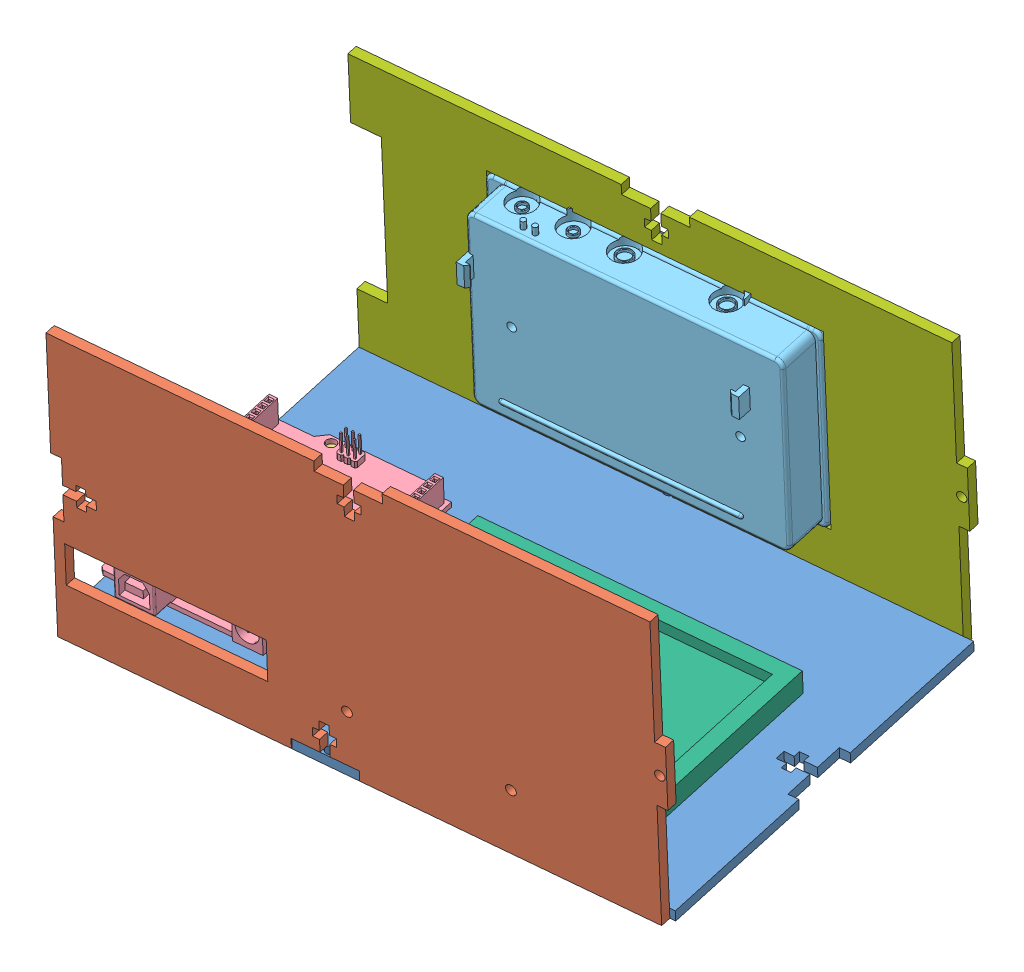
SolidWorks assembly PIDbox.testassembly1, configuration Default. Lengths in mm.
Overall size (201.49 115.17 154.94).
10 component instances, 7 part files, 34 mates.
Components (placement in the parent):
- PIDbox.floor-1: PIDbox.floor [Default] at (-69.6794 29.4727 44.4272) x (0.989177 -0.043479 -0.140136) z (0.057614 0.993474 0.09844) size (180 122.36 3.18)
- PIDbox.frontwall-2: PIDbox.frontwall [Default] at (-57.667 70.483 106.041) x (0.989177 -0.043479 -0.140136) z (0.134941 -0.105448 0.985227) size (180 95 3.18)
- 25x.5 Aluminum Hex Female Female Standoff-1: 25x.5 Aluminum Hex Female Female Standoff [Default] at (-135.3438 43.3038 40.0823) x (0.981916 -0.074202 0.174172) z (0.057614 0.993474 0.09844) size (6.35 8.06 12.7)
- 25x.5 Aluminum Hex Female Female Standoff-2: 25x.5 Aluminum Hex Female Female Standoff [Default] at (-107.7458 42.0908 36.1726) x (0.981916 -0.074202 0.174172) z (0.057614 0.993474 0.09844) size (6.35 8.06 12.7)
- 25x.5 Aluminum Hex Female Female Standoff-3: 25x.5 Aluminum Hex Female Female Standoff [Default] at (-95.6301 36.3435 87.0838) x (0.981916 -0.074202 0.174172) z (0.057614 0.993474 0.09844) size (6.35 8.06 12.7)
- 25x.5 Aluminum Hex Female Female Standoff-4: 25x.5 Aluminum Hex Female Female Standoff [Default] at (-143.6233 38.6123 92.2759) x (0.981916 -0.074202 0.174172) z (0.057614 0.993474 0.09844) size (6.35 8.06 12.7)
- ArduinoUno-1: ArduinoUno [Default] at (-121.7167 45.7056 72.3738) x (-0.134941 0.105448 -0.985227) z (0.989177 -0.043479 -0.140136) size (74.8 12.1 53.3)
- 6AA Battery Holder-1: 6AA Battery Holder [Default] at (-81.7483 84.0491 -12.2058) x (0.989177 -0.043479 -0.140136) z (-0.057614 -0.993474 -0.09844) size (114.4 23.95 66)
- PIDbox.breadboardholder-1: PIDbox.breadboardholder [Default] at (-47.1792 30.421 53.9923) x (0.989177 -0.043479 -0.140136) z (0.057614 0.993474 0.09844) size (95 78.44 20)
- PIDbox.backwall-1: PIDbox.backwall [Default] at (-75.0747 83.1086 -11.1906) x (0.989177 -0.043479 -0.140136) z (0.134941 -0.105448 0.985227) size (180 95 3.18)
Mates (geometry in assembly coordinates):
- Perpendicular2: perpendicular: plane of PIDbox.floor-1 through (-69.4961 32.6319 44.7403) normal (0.057614 0.993474 0.09844); plane of PIDbox.frontwall-2 through (-57.667 70.483 106.041) normal (-0.134941 0.105448 -0.985227)
- Parallel2: parallel aligned: plane of PIDbox.floor-1 through (11.2741 35.1701 -28.1481) normal (0.989177 -0.043479 -0.140136); plane of PIDbox.frontwall-2 through (25.4767 19.5181 89.1985) normal (0.989177 -0.043479 -0.140136)
- Coincident9: coincident anti-aligned: plane of PIDbox.floor-1 through (-61.5473 23.0268 104.7209) normal (0.989177 -0.043479 -0.140136); plane of PIDbox.frontwall-2 through (-61.9764 23.3621 101.5879) normal (-0.989177 0.043479 0.140136)
- Coincident10: coincident aligned: plane of PIDbox.floor-1 through (-69.6794 29.4727 44.4272) normal (-0.057614 -0.993474 -0.09844); plane of PIDbox.frontwall-2 through (-149.0005 26.8708 117.1103) normal (-0.057614 -0.993474 -0.09844)
- Coincident12: coincident aligned: plane of PIDbox.floor-1 through (-150.2664 30.0937 117.6287) normal (0.134941 -0.105448 0.985227); plane of PIDbox.frontwall-2 through (-57.2379 70.1477 109.174) normal (0.134941 -0.105448 0.985227)
- Concentric1: concentric aligned: cylinder of PIDbox.floor-1 through (-135.8929 33.836 39.1442) axis (0.057614 0.993474 0.09844) radius 1.6; cylinder of 25x.5 Aluminum Hex Female Female Standoff-1 through (-134.978 49.6124 40.7074) axis (0.057614 0.993474 0.09844) radius 1.0287
- Coincident13: coincident anti-aligned: plane of PIDbox.floor-1 through (-69.4961 32.6319 44.7403) normal (0.057614 0.993474 0.09844); plane of 25x.5 Aluminum Hex Female Female Standoff-1 through (-135.7097 36.9953 39.4573) normal (-0.057614 -0.993474 -0.09844)
- Concentric2: concentric aligned: circle of PIDbox.floor-1; cylinder of 25x.5 Aluminum Hex Female Female Standoff-2 through (-107.38 48.3993 36.7977) axis (0.057614 0.993474 0.09844) radius 1.0287
- Coincident14: coincident anti-aligned: plane of PIDbox.floor-1 through (-69.4961 32.6319 44.7403) normal (0.057614 0.993474 0.09844); plane of 25x.5 Aluminum Hex Female Female Standoff-2 through (-108.1117 35.7822 35.5475) normal (-0.057614 -0.993474 -0.09844)
- Concentric3: concentric aligned: cylinder of PIDbox.floor-1 through (-96.1791 26.8757 86.1456) axis (0.057614 0.993474 0.09844) radius 1.6; cylinder of 25x.5 Aluminum Hex Female Female Standoff-3 through (-95.2642 42.6521 87.7088) axis (0.057614 0.993474 0.09844) radius 1.0287
- Coincident15: coincident anti-aligned: plane of PIDbox.floor-1 through (-69.4961 32.6319 44.7403) normal (0.057614 0.993474 0.09844); plane of 25x.5 Aluminum Hex Female Female Standoff-3 through (-95.9959 30.035 86.4587) normal (-0.057614 -0.993474 -0.09844)
- Concentric4: concentric aligned: cylinder of PIDbox.floor-1 through (-144.1723 29.1445 91.3378) axis (0.057614 0.993474 0.09844) radius 1.6; cylinder of 25x.5 Aluminum Hex Female Female Standoff-4 through (-143.2574 44.9209 92.901) axis (0.057614 0.993474 0.09844) radius 1.0287
- Coincident16: coincident anti-aligned: plane of PIDbox.floor-1 through (-69.4961 32.6319 44.7403) normal (0.057614 0.993474 0.09844); plane of 25x.5 Aluminum Hex Female Female Standoff-4 through (-143.9891 32.3037 91.6508) normal (-0.057614 -0.993474 -0.09844)
- Parallel4: parallel anti-aligned: plane of PIDbox.floor-1 through (-69.4961 32.6319 44.7403) normal (0.057614 0.993474 0.09844); plane of ArduinoUno-1 through (-152.5314 50.3441 43.5959) normal (-0.057614 -0.993474 -0.09844)
- Concentric5: concentric aligned: cone of 25x.5 Aluminum Hex Female Female Standoff-2 through (-107.38 48.3993 36.7977) axis (-0.057614 -0.993474 -0.09844); cylinder of ArduinoUno-1 through (-107.2878 49.9889 36.9552) axis (-0.057614 -0.993474 -0.09844) radius 1.6
- Coincident20: coincident aligned: circle of 25x.5 Aluminum Hex Female Female Standoff-2; plane of ArduinoUno-1 through (-152.5314 50.3441 43.5959) normal (-0.057614 -0.993474 -0.09844)
- Concentric6: concentric anti-aligned: cylinder of 25x.5 Aluminum Hex Female Female Standoff-4 through (-143.2574 44.9209 92.901) axis (0.057614 0.993474 0.09844) radius 1.0287; cylinder of ArduinoUno-1 through (-143.1652 46.5104 93.0585) axis (-0.057614 -0.993474 -0.09844) radius 1.6
- Parallel7: parallel anti-aligned: plane of PIDbox.frontwall-2 through (-57.667 70.483 106.041) normal (-0.134941 0.105448 -0.985227); plane of 6AA Battery Holder-1 through (-81.4785 83.8382 -10.2354) normal (0.134941 -0.105448 0.985227)
- Coincident23: coincident anti-aligned: plane of PIDbox.floor-1 through (-166.7778 42.9964 -2.9237) normal (-0.134941 0.105448 -0.985227); plane of 6AA Battery Holder-1 through (-81.4785 83.8382 -10.2354) normal (0.134941 -0.105448 0.985227)
- Parallel8: parallel anti-aligned: plane of PIDbox.frontwall-2 through (-57.667 70.483 106.041) normal (-0.134941 0.105448 -0.985227); plane of PIDbox.breadboardholder-1 through (-42.3498 33.9166 86.9969) normal (0.134941 -0.105448 0.985227)
- Coincident25: coincident anti-aligned: plane of PIDbox.frontwall-2 through (-57.667 70.483 106.041) normal (-0.134941 0.105448 -0.985227); plane of PIDbox.breadboardholder-1 through (-39.8682 45.4778 100.9269) normal (0.134941 -0.105448 0.985227)
- Coincident26: coincident anti-aligned: plane of PIDbox.floor-1 through (-69.4961 32.6319 44.7403) normal (0.057614 0.993474 0.09844); plane of PIDbox.breadboardholder-1 through (-47.1792 30.421 53.9923) normal (-0.057614 -0.993474 -0.09844)
- Parallel9: parallel aligned: plane of PIDbox.floor-1 through (6.2849 26.2829 32.1589) normal (0.989177 -0.043479 -0.140136); plane of PIDbox.breadboardholder-1 through (0.21 35.31 48.025) normal (0.989177 -0.043479 -0.140136)
- Coincident28: coincident aligned: plane of PIDbox.frontwall-2 through (-67.8299 33.5795 103.4832) normal (-0.989177 0.043479 0.140136); plane of PIDbox.breadboardholder-1 through (-74.1799 35.0938 58.1906) normal (-0.989177 0.043479 0.140136)
- Parallel10: parallel anti-aligned: plane of PIDbox.floor-1 through (-69.4961 32.6319 44.7403) normal (0.057614 0.993474 0.09844); plane of 6AA Battery Holder-1 through (-120.2507 54.0203 8.631) normal (-0.057614 -0.993474 -0.09844)
- Perpendicular3: perpendicular: plane of PIDbox.floor-1 through (-69.4961 32.6319 44.7403) normal (0.057614 0.993474 0.09844); plane of PIDbox.backwall-1 through (-74.6456 82.7732 -8.0575) normal (0.134941 -0.105448 0.985227)
- Parallel11: parallel aligned: plane of PIDbox.frontwall-2 through (-143.5271 121.2508 126.4621) normal (-0.989177 0.043479 0.140136); plane of PIDbox.backwall-1 through (-160.9349 133.8764 9.2305) normal (-0.989177 0.043479 0.140136)
- Coincident32: coincident anti-aligned: plane of PIDbox.floor-1 through (-69.4961 32.6319 44.7403) normal (0.057614 0.993474 0.09844); plane of PIDbox.backwall-1 through (-87.52 39.5126 -14.1521) normal (-0.057614 -0.993474 -0.09844)
- Coincident33: coincident anti-aligned: plane of PIDbox.floor-1 through (-87.7032 36.3533 -14.4651) normal (-0.989177 0.043479 0.140136); plane of PIDbox.backwall-1 through (-87.7032 36.3533 -14.4651) normal (0.989177 -0.043479 -0.140136)
- Coincident34: coincident aligned: plane of PIDbox.floor-1 through (-166.7778 42.9964 -2.9237) normal (-0.134941 0.105448 -0.985227); plane of PIDbox.backwall-1 through (-75.0747 83.1086 -11.1906) normal (-0.134941 0.105448 -0.985227)
- Coincident35: coincident anti-aligned: plane of 6AA Battery Holder-1 through (-81.4785 83.8382 -10.2354) normal (0.134941 -0.105448 0.985227); plane of PIDbox.backwall-1 through (-75.0747 83.1086 -11.1906) normal (-0.134941 0.105448 -0.985227)
- Coincident37: coincident anti-aligned: plane of 6AA Battery Holder-1 through (-81.4785 83.8382 -10.2354) normal (0.134941 -0.105448 0.985227); plane of PIDbox.backwall-1 through (-75.0747 83.1086 -11.1906) normal (-0.134941 0.105448 -0.985227)
- Coincident38: coincident anti-aligned: plane of 6AA Battery Holder-1 through (-122.1848 116.0558 2.8481) normal (0.057614 0.993474 0.09844); plane of PIDbox.backwall-1 through (-24.7625 111.8552 -11.7771) normal (-0.057614 -0.993474 -0.09844)
- Coincident39: coincident anti-aligned: plane of 6AA Battery Holder-1 through (-24.6519 111.7688 -10.9692) normal (0.989177 -0.043479 -0.140136); plane of PIDbox.backwall-1 through (-24.7625 111.8552 -11.7771) normal (-0.989177 0.043479 0.140136)
